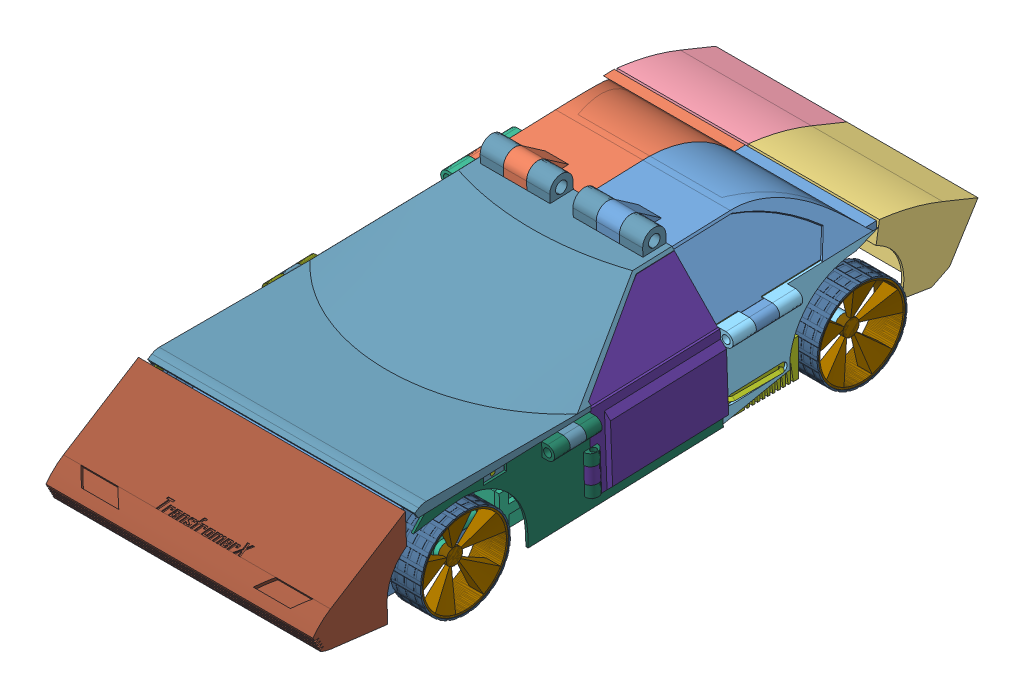
SolidWorks assembly TransformerX_CarMode, configuration Default. Lengths in mm.
Overall size (126 89.14 292.38).
45 component instances, 25 part files, 125 mates.
Components (placement in the parent):
- Body-1: Body [Default] at (-0.7166 15 158.0396) x (1 0 0) z (0 -1 0) size (90 111.5 41.19)
- Leg2_left-1: Leg2_left [Default] at (34.7834 15 123.3396) x (1 0 0) z (0 -1 0) size (33 44.2 22.31)
- Leg2_right-1: Leg2_right [Default] at (-36.2166 15 123.3396) x (1 0 0) z (0 -1 0) size (33 44.2 22.31)
- Head-1: Head [Default] at (-0.7166 15 243.0396) x (1 0 0) z (0 -1 0) size (26 20 18.29)
- Axis-1: Axis [Default] at (34.7834 15 116.1396) x (0 -1 0) z (-1 0 0) size (7 7 39)
- Axis-2: Axis [Default] at (-36.2166 15 116.1396) x (0 -0.62043 -0.784262) z (-1 0 0) size (7 7 39)
- Arm-4: Arm [Default] at (-45.2166 18.6049 182.2607) x (-1 0 0) z (0 0.981511 0.191408) size (24 60 17)
- Arm-5: Arm [Default] at (43.7834 12.2258 181.5547) x (1 0 0) z (0 -0.999612 -0.027841) size (24 60 17)
- Leg1-1: Leg1 [Default] at (34.7834 11 91.5396) x (1 0 0) z (0 -1 0) size (44.5 80.02 25)
- Leg1-2: Leg1 [Default] at (-36.2166 11 91.5396) x (1 0 0) z (0 -1 0) size (44.5 80.02 25)
- Axis-3: Axis [Default] at (-36.2166 11 49.6396) x (0 0.287561 -0.957762) z (-1 0 0) size (7 7 39)
- Axis-4: Axis [Default] at (34.7834 11 49.6396) x (0 -0.62043 -0.784262) z (-1 0 0) size (7 7 39)
- Locker-1: Locker [Default] at (51.2834 15 116.1396) x (0 0.975545 0.219799) z (1 0 0) size (9 9 4)
- Locker-2: Locker [Default] at (-52.7166 15 116.1396) x (0 -0.822687 -0.568495) z (-1 0 0) size (9 9 4)
- Locker-3: Locker [Default] at (-19.7166 15 116.1396) x (0 0.518621 0.855004) z (1 0 0) size (9 9 4)
- Locker-4: Locker [Default] at (18.2834 15 116.1396) x (0 0.991738 -0.128282) z (-1 0 0) size (9 9 4)
- Wheel-1: Wheel [Default] at (-54.4666 11 49.6396) x (0 0.974851 0.222857) z (-1 0 0) size (37.5 37.5 12.5)
- Wheel-2: Wheel [Default] at (-17.9666 11 49.6396) x (0 0.657679 0.753298) z (1 0 0) size (37.5 37.5 12.5)
- Wheel-3: Wheel [Default] at (16.5334 11 49.6396) x (0 -0.657679 -0.753298) z (-1 0 0) size (37.5 37.5 12.5)
- Wheel-4: Wheel [Default] at (53.0334 11 49.6396) x (0 0.657679 0.753298) z (1 0 0) size (37.5 37.5 12.5)
- Wheel-5: Wheel [Default] at (53.0334 11.14 220.5396) x (0 -0.683817 0.729653) z (1 0 0) size (37.5 37.5 12.5)
- Wheel-6: Wheel [Default] at (-54.4666 11.14 220.5396) x (0 0.512398 -0.858748) z (-1 0 0) size (37.5 37.5 12.5)
- Tire-1: Tire [Default] at (16.5334 11 49.6396) x (0 -0.314731 -0.949181) z (1 0 0) size (38.8 38.79 13)
- Tire-2: Tire [Default] at (-54.4666 11 49.6396) x (0 0.805468 -0.59264) z (1 0 0) size (38.8 38.79 13)
- Tire-3: Tire [Default] at (-17.9666 11 49.6396) x (0 0.068791 0.997631) z (-1 0 0) size (38.8 38.79 13)
- Tire-4: Tire [Default] at (-54.4666 11.14 220.5396) x (0 0.968779 -0.247928) z (1 0 0) size (38.8 38.79 13)
- Tire-5: Tire [Default] at (53.0334 11 49.6396) x (0 0.314731 0.949181) z (-1 0 0) size (38.8 38.79 13)
- Tire-6: Tire [Default] at (53.0334 11.14 220.5396) x (0 -0.756586 0.653895) z (-1 0 0) size (38.8 38.79 13)
- CarPart1-1: CarPart1 [Default] at (-0.7166 21.0613 251.9185) x (0 -0.03628 0.999342) z (-1 0 0) size (40.79 38 115)
- Axis3-1: Axis3 [Default] at (45.0334 30 247.0396) x (0 1 0) z (1 0 0) size (8 8 19.5)
- Axis3-2: Axis3 [Default] at (-46.4666 30 247.0396) x (0 -0.381849 0.924225) z (-1 0 0) size (8 8 19.5)
- Locker2-2: Locker2 [Default] at (-36.7166 30 247.0396) x (0 -0.99661 0.082275) z (-1 0 0) size (8 8 4)
- Locker2-3: Locker2 [Default] at (35.2834 30 247.0396) x (0 0.456595 -0.889675) z (1 0 0) size (8 8 4)
- CarPart2-1: CarPart2 [Default] at (-0.7166 37.5573 174.212) x (0 -0.03628 0.999342) z (-1 0 0) size (131.64 36.94 126)
- CarPart3_left-1: CarPart3_left [Default] at (56.2834 7.3112 163.3576) x (0 -0.03628 0.999342) z (-1 0 0) size (132.4 36.62 6.5)
- CarPart3_right-1: CarPart3_right [Default] at (-57.7166 7.3112 163.3576) x (0 -0.03628 0.999342) z (-1 0 0) size (132.4 36.62 6.5)
- CarPart_Door_left-1: CarPart_Door_left [Default] at (56.7834 22.7866 135.6508) x (0 -0.03628 0.999342) z (-1 0 0) size (59.5 53.92 22.75)
- CarPart_Door_right-1: CarPart_Door_right [Default] at (-57.2166 22.7866 135.6508) x (0 -0.03628 0.999342) z (-1 0 0) size (59.5 53.92 22.75)
- CarPart4_left-1: CarPart4_left [Default] at (27.5334 42.2028 73.8145) x (0 -0.03628 0.999342) z (-1 0 0) size (78.5 35.5 63)
- CarPart4_right-1: CarPart4_right [Default] at (-28.9666 42.2028 73.8145) x (0 -0.03628 0.999342) z (-1 0 0) size (78.5 35.5 63)
- CarPart5_left-1: CarPart5_left [Default] at (27.5334 41.5302 25.0024) x (0 -0.158579 -0.987346) z (1 0 0) size (48.5 32.62 56.5)
- CarPart5_right-1: CarPart5_right [Default] at (-28.9666 41.5302 25.0024) x (0 -0.158579 -0.987346) z (1 0 0) size (48.5 32.62 56.5)
- CarPart6_left-1: CarPart6_left [Default] at (55.7834 23.4142 72.8822) x (0 -0.03628 0.999342) z (-1 0 0) size (69 37.62 7.5)
- CarPart6_right-1: CarPart6_right [Default] at (-56.2166 23.4142 72.8822) x (0 -0.03628 0.999342) z (-1 0 0) size (69 37.62 7.5)
- Axis4-1: Axis4 [Default] at (-0.7166 35 205.0396) x (0 0 1) z (-1 0 0) size (5.5 5.5 113)
Mates (geometry in assembly coordinates):
- Concentric1: concentric aligned: cylinder of Body-1 through (27.2834 15 147.8396) axis (-1 0 0) radius 3.5; cylinder of Leg2_left-1 through (27.2834 15 147.8396) axis (-1 0 0) radius 3.5
- Coincident1: coincident anti-aligned: plane of Body-1 through (27.2834 15 147.8396) normal (1 0 0); plane of Leg2_left-1 through (27.2834 15 147.8396) normal (-1 0 0)
- Concentric2: concentric aligned: cylinder of Body-1 through (-28.7166 15 147.8396) axis (1 0 0) radius 3.5; cylinder of Leg2_right-1 through (-28.7166 15 147.8396) axis (1 0 0) radius 3.5
- Coincident2: coincident anti-aligned: plane of Body-1 through (-28.7166 15 147.8396) normal (-1 0 0); plane of Leg2_right-1 through (-28.7166 15 147.8396) normal (1 0 0)
- Parallel1: parallel aligned: plane of Leg2_left-1 through (18.2834 25 155.3396) normal (0 1 0); plane of Leg2_right-1 through (-52.7166 25 155.3396) normal (0 1 0)
- Parallel2: parallel aligned: plane of Body-1 through (44.2834 30 243.0396) normal (0 1 0); plane of Leg2_right-1 through (-52.7166 25 155.3396) normal (0 1 0)
- Concentric3: concentric aligned: cylinder of Body-1 through (-0.7166 15 250.0396) axis (0 0 -1) radius 4.5; cylinder of Head-1 through (-0.7166 15 250.0396) axis (0 0 -1) radius 4.5
- Coincident5: coincident anti-aligned: plane of Body-1 through (-0.7166 15 250.0396) normal (0 0 1); plane of Head-1 through (-0.7166 15 250.0396) normal (0 0 -1)
- Parallel3: parallel aligned: plane of Body-1 through (-45.7166 0 243.0396) normal (0 -1 0); plane of Head-1 through (-0.7166 4.5 243.0396) normal (0 -1 0)
- Concentric4: concentric anti-aligned: cylinder of Leg2_right-1 through (-19.7166 15 116.1396) axis (-1 0 0) radius 3.5; cylinder of Axis-2 through (-14.84 15 116.1396) axis (1 0 0) radius 3.5
- Coincident7: coincident aligned: plane of Leg2_right-1 through (-19.7166 25 155.3396) normal (1 0 0); plane of Axis-2 through (-19.7166 13.4489 114.1789) normal (1 0 0)
- Concentric5: concentric anti-aligned: cylinder of Leg2_left-1 through (51.2834 15 116.1396) axis (-1 0 0) radius 3.5; cylinder of Axis-1 through (56.16 15 116.1396) axis (1 0 0) radius 3.5
- Coincident8: coincident aligned: plane of Leg2_left-1 through (51.2834 25 155.3396) normal (1 0 0); plane of Axis-1 through (51.2834 12.5 116.1396) normal (1 0 0)
- Concentric6: concentric aligned: cylinder of Body-1 through (30.2834 11.14 220.5396) axis (1 0 0) radius 3.5; cylinder of Arm-5 through (30.2834 11.14 220.5396) axis (1 0 0) radius 3.5
- Coincident9: coincident anti-aligned: plane of Body-1 through (39.2834 30.0011 158.0396) normal (1 0 0); plane of Arm-5 through (39.2834 12.2258 181.5547) normal (-1 0 0)
- Concentric7: concentric aligned: cylinder of Body-1 through (-31.7166 11.14 220.5396) axis (-1 0 0) radius 3.5; cylinder of Arm-4 through (-31.7166 11.14 220.5396) axis (-1 0 0) radius 3.5
- Coincident10: coincident anti-aligned: plane of Body-1 through (-40.7166 30.0011 158.0396) normal (-1 0 0); plane of Arm-4 through (-40.7166 18.6049 182.2607) normal (1 0 0)
- Concentric8: concentric aligned: cylinder of Axis-1 through (56.16 15 116.1396) axis (1 0 0) radius 3.5; cylinder of Leg1-1 through (15.0324 15 116.1396) axis (1 0 0) radius 3.75
- Coincident11: coincident anti-aligned: plane of Leg2_left-1 through (46.7834 15 123.3396) normal (-1 0 0); plane of Leg1-1 through (46.7834 15 116.1396) normal (1 0 0)
- Concentric9: concentric anti-aligned: cylinder of Axis-2 through (-14.84 15 116.1396) axis (1 0 0) radius 3.5; cylinder of Leg1-2 through (-16.4656 15 116.1396) axis (-1 0 0) radius 3.75
- Coincident12: coincident anti-aligned: plane of Leg2_right-1 through (-24.2166 15 123.3396) normal (-1 0 0); plane of Leg1-2 through (-24.2166 15 116.1396) normal (1 0 0)
- Parallel4: parallel aligned: plane of Leg1-1 through (20.7834 19 61.9396) normal (0 1 0); plane of Leg1-2 through (-50.2166 19 61.9396) normal (0 1 0)
- Parallel5: parallel aligned: plane of Leg2_left-1 through (18.2834 25 155.3396) normal (0 1 0); plane of Leg1-1 through (20.7834 19 61.9396) normal (0 1 0)
- Concentric10: concentric anti-aligned: cylinder of Leg1-2 through (-16.4656 11 49.6396) axis (-1 0 0) radius 3.5; cylinder of Axis-3 through (-14.84 11 49.6396) axis (1 0 0) radius 3.5
- Width2: width aligned: plane of Leg1-2 through (-32.2166 3 44.1396) normal (1 0 0); plane of Leg1-2 through (-40.2166 3 44.1396) normal (-1 0 0); plane of Axis-3 through (-19.7166 11.7189 47.2452) normal (1 0 0); plane of Axis-3 through (-52.7166 12.0065 46.2874) normal (-1 0 0)
- Concentric11: concentric anti-aligned: cylinder of Leg1-1 through (54.5344 11 49.6396) axis (-1 0 0) radius 3.5; cylinder of Axis-4 through (56.16 11 49.6396) axis (1 0 0) radius 3.5
- Width3: width aligned: plane of Leg1-1 through (30.7834 3 44.1396) normal (-1 0 0); plane of Leg1-1 through (38.7834 3 44.1396) normal (1 0 0); plane of Axis-4 through (18.2834 8.8285 46.8946) normal (-1 0 0); plane of Axis-4 through (51.2834 9.4489 47.6789) normal (1 0 0)
- Concentric12: concentric aligned: cylinder of Axis-2 through (-14.84 15 116.1396) axis (1 0 0) radius 2.5; cylinder of Locker-2 through (-56.7166 15 116.1396) axis (1 0 0) radius 4.5
- Coincident15: coincident anti-aligned: plane of Leg2_right-1 through (-52.7166 25 155.3396) normal (-1 0 0); plane of Locker-2 through (-52.7166 15 116.1396) normal (1 0 0)
- Concentric13: concentric anti-aligned: cylinder of Axis-1 through (56.16 15 116.1396) axis (1 0 0) radius 2.5; cylinder of Locker-1 through (55.2834 15 116.1396) axis (-1 0 0) radius 4.5
- Coincident16: coincident anti-aligned: plane of Leg2_left-1 through (51.2834 25 155.3396) normal (1 0 0); plane of Locker-1 through (51.2834 15 116.1396) normal (-1 0 0)
- Concentric14: concentric anti-aligned: cylinder of Axis-2 through (-14.84 15 116.1396) axis (1 0 0) radius 2.5; cylinder of Locker-3 through (-15.7166 15 116.1396) axis (-1 0 0) radius 4.5
- Coincident17: coincident anti-aligned: plane of Leg2_right-1 through (-19.7166 25 155.3396) normal (1 0 0); plane of Locker-3 through (-19.7166 15 116.1396) normal (-1 0 0)
- Concentric15: concentric aligned: cylinder of Axis-1 through (56.16 15 116.1396) axis (1 0 0) radius 2.5; cylinder of Locker-4 through (15.2834 15 116.1396) axis (1 0 0) radius 2.5
- Coincident18: coincident anti-aligned: plane of Leg2_left-1 through (18.2834 25 155.3396) normal (-1 0 0); plane of Locker-4 through (18.2834 15 116.1396) normal (1 0 0)
- Concentric16: concentric aligned: cylinder of Axis-3 through (-14.84 11 49.6396) axis (1 0 0) radius 2.5; cylinder of Wheel-1 through (-55.7166 11 49.6396) axis (1 0 0) radius 2.5
- Coincident19: coincident anti-aligned: plane of Axis-3 through (-52.7166 12.0065 46.2874) normal (-1 0 0); plane of Wheel-1 through (-52.7166 7.588 48.8596) normal (1 0 0)
- Concentric17: concentric anti-aligned: cylinder of Axis-3 through (-14.84 11 49.6396) axis (1 0 0) radius 2.5; cylinder of Wheel-2 through (-16.7166 11 49.6396) axis (-1 0 0) radius 2.5
- Coincident20: coincident anti-aligned: plane of Axis-3 through (-19.7166 11.7189 47.2452) normal (1 0 0); plane of Wheel-2 through (-19.7166 8.6981 47.003) normal (-1 0 0)
- Concentric18: concentric aligned: cylinder of Axis-4 through (56.16 11 49.6396) axis (1 0 0) radius 2.5; cylinder of Wheel-3 through (15.2834 11 49.6396) axis (1 0 0) radius 2.5
- Coincident21: coincident anti-aligned: plane of Axis-4 through (18.2834 8.8285 46.8946) normal (-1 0 0); plane of Wheel-3 through (18.2834 13.3019 52.2761) normal (1 0 0)
- Concentric19: concentric anti-aligned: cylinder of Axis-4 through (56.16 11 49.6396) axis (1 0 0) radius 2.5; cylinder of Wheel-4 through (54.2834 11 49.6396) axis (-1 0 0) radius 2.5
- Coincident22: coincident anti-aligned: plane of Axis-4 through (51.2834 9.4489 47.6789) normal (1 0 0); plane of Wheel-4 through (51.2834 8.6981 47.003) normal (-1 0 0)
- Concentric20: concentric aligned: cylinder of Arm-4 through (-55.7166 11.14 220.5396) axis (1 0 0) radius 2.5; cylinder of Wheel-6 through (-55.7166 11.14 220.5396) axis (1 0 0) radius 2.5
- Coincident23: coincident anti-aligned: plane of Arm-4 through (-52.7166 11.14 220.5396) normal (-1 0 0); plane of Wheel-6 through (-52.7166 9.3466 223.5452) normal (1 0 0)
- Concentric21: concentric aligned: cylinder of Arm-5 through (54.2834 11.14 220.5396) axis (-1 0 0) radius 2.5; cylinder of Wheel-5 through (54.2834 11.14 220.5396) axis (-1 0 0) radius 2.5
- Coincident24: coincident anti-aligned: plane of Arm-5 through (51.2834 11.14 220.5396) normal (1 0 0); plane of Wheel-5 through (51.2834 13.5334 217.9858) normal (-1 0 0)
- Parallel6: parallel aligned: plane of Wheel-3 through (16.5334 11.639 49.5848) normal (0 -0.996343 0.085446); plane of Wheel-4 through (53.0334 11.639 49.5848) normal (0 -0.996343 0.085446)
- Parallel7: parallel aligned: plane of Wheel-1 through (-54.4666 11.639 49.5848) normal (0 -0.996343 0.085446); plane of Wheel-2 through (-17.9666 11.639 49.5848) normal (0 -0.996343 0.085446)
- Parallel8: parallel aligned: plane of Wheel-2 through (-17.9666 11.639 49.5848) normal (0 -0.996343 0.085446); plane of Wheel-3 through (16.5334 11.639 49.5848) normal (0 -0.996343 0.085446)
- Concentric22: concentric anti-aligned: cylinder of Wheel-1 through (-19.3072 11 49.6396) axis (1 0 0) radius 18.75; cylinder of Tire-2 through (-47.9656 11 49.6396) axis (-1 0 0) radius 18.75
- Width4: width aligned: plane of Wheel-1 through (-60.7166 11 49.6396) normal (-1 0 0); plane of Wheel-1 through (-48.2166 -7.2785 45.461) normal (1 0 0); plane of Tire-2 through (-60.9666 11 49.6396) normal (-1 0 0); plane of Tire-2 through (-47.9666 11 49.6396) normal (1 0 0)
- Concentric23: concentric anti-aligned: cylinder of Wheel-2 through (-53.126 11 49.6396) axis (-1 0 0) radius 18.75; cylinder of Tire-3 through (-24.4676 11 49.6396) axis (1 0 0) radius 18.75
- Width5: width aligned: plane of Wheel-2 through (-11.7166 11 49.6396) normal (1 0 0); plane of Wheel-2 through (-24.2166 -1.3315 35.5152) normal (-1 0 0); plane of Tire-3 through (-11.4666 11 49.6396) normal (1 0 0); plane of Tire-3 through (-24.4666 11 49.6396) normal (-1 0 0)
- Concentric24: concentric anti-aligned: cylinder of Wheel-3 through (51.6928 11 49.6396) axis (1 0 0) radius 18.75; cylinder of Tire-1 through (23.0344 11 49.6396) axis (-1 0 0) radius 18.75
- Width6: width aligned: plane of Wheel-3 through (22.7834 23.3315 63.7639) normal (1 0 0); plane of Wheel-3 through (10.2834 11 49.6396) normal (-1 0 0); plane of Tire-1 through (23.0334 11 49.6396) normal (1 0 0); plane of Tire-1 through (10.0334 11 49.6396) normal (-1 0 0)
- Concentric25: concentric anti-aligned: cylinder of Wheel-4 through (17.874 11 49.6396) axis (-1 0 0) radius 18.75; cylinder of Tire-5 through (46.5324 11 49.6396) axis (1 0 0) radius 18.75
- Width7: width aligned: plane of Wheel-4 through (46.7834 -1.3315 35.5152) normal (-1 0 0); plane of Wheel-4 through (59.2834 11 49.6396) normal (1 0 0); plane of Tire-5 through (46.5334 11 49.6396) normal (-1 0 0); plane of Tire-5 through (59.5334 11 49.6396) normal (1 0 0)
- Concentric26: concentric anti-aligned: cylinder of Wheel-6 through (-19.3072 11.14 220.5396) axis (1 0 0) radius 18.75; cylinder of Tire-4 through (-47.9656 11.14 220.5396) axis (-1 0 0) radius 18.75
- Concentric27: concentric anti-aligned: cylinder of Wheel-5 through (17.874 11.14 220.5396) axis (-1 0 0) radius 18.75; cylinder of Tire-6 through (46.5324 11.14 220.5396) axis (1 0 0) radius 18.75
- Width8: width anti-aligned: plane of Wheel-5 through (59.2834 11.14 220.5396) normal (1 0 0); plane of Wheel-5 through (46.7834 23.9616 206.8586) normal (-1 0 0); plane of Tire-6 through (46.5334 11.14 220.5396) normal (-1 0 0); plane of Tire-6 through (59.5334 11.14 220.5396) normal (1 0 0)
- Width9: width aligned: plane of Wheel-6 through (-60.7166 11.14 220.5396) normal (-1 0 0); plane of Wheel-6 through (-48.2166 1.5325 236.6411) normal (1 0 0); plane of Tire-4 through (-60.9666 11.14 220.5396) normal (-1 0 0); plane of Tire-4 through (-47.9666 11.14 220.5396) normal (1 0 0)
- Parallel9: parallel aligned: plane of Wheel-4 through (53.0334 11.6386 49.5798) normal (0 -0.995653 0.093145); plane of Tire-5 through (53.0334 11 49.6396) normal (0 -0.995653 0.093145)
- Parallel10: parallel aligned: plane of Wheel-3 through (16.5334 11.6386 49.5798) normal (0 -0.995653 0.093145); plane of Tire-1 through (16.5334 11 49.6396) normal (0 -0.995653 0.093145)
- Parallel11: parallel aligned: plane of Wheel-2 through (-17.9666 11.6386 49.5798) normal (0 -0.995653 0.093145); plane of Tire-3 through (-17.9666 11 49.6396) normal (0 -0.995653 0.093145)
- Parallel12: parallel aligned: plane of Wheel-1 through (-54.4666 11.2541 50.2284) normal (0 -0.39626 -0.918139); plane of Tire-2 through (-54.4666 11 49.6396) normal (0 -0.39626 -0.918139)
- Parallel13: parallel aligned: plane of Wheel-5 through (53.0334 11.4147 219.96) normal (0 -0.428369 0.903604); plane of Tire-6 through (53.0334 11.14 220.5396) normal (0 -0.428369 0.903604)
- Parallel14: parallel anti-aligned: plane of Wheel-6 through (-54.4666 11.2848 219.9147) normal (0 -0.225718 0.974193); plane of Tire-4 through (-54.4666 11.14 220.5396) normal (0 0.225718 -0.974193)
- Concentric28: concentric anti-aligned: cylinder of Body-1 through (-45.7877 30 247.0396) axis (1 0 0) radius 2.5; cylinder of CarPart1-1 through (54.7834 30 247.0396) axis (-1 0 0) radius 2.5
- Width10: width anti-aligned: plane of Body-1 through (44.2834 0 243.0396) normal (1 0 0); plane of Body-1 through (-45.7166 30 243.0396) normal (-1 0 0); plane of CarPart1-1 through (-58.2166 10.8466 231.5345) normal (-1 0 0); plane of CarPart1-1 through (56.7834 10.8466 231.5345) normal (1 0 0)
- Concentric30: concentric aligned: cylinder of CarPart1-1 through (54.7834 30 247.0396) axis (-1 0 0) radius 2.5; cylinder of Axis3-1 through (16.5008 30 247.0396) axis (-1 0 0) radius 2.5
- Coincident36: coincident anti-aligned: plane of Body-1 through (41.2834 30 247.0396) normal (1 0 0); plane of Axis3-1 through (41.2834 32.5 247.0396) normal (-1 0 0)
- Concentric31: concentric anti-aligned: cylinder of Body-1 through (-31.6456 30 247.0396) axis (-1 0 0) radius 2.5; cylinder of Axis3-2 through (-17.934 30 247.0396) axis (1 0 0) radius 2.5
- Coincident37: coincident anti-aligned: plane of CarPart1-1 through (-54.2166 29.9565 248.2388) normal (1 0 0); plane of Axis3-2 through (-54.2166 28.4726 250.7365) normal (-1 0 0)
- Concentric32: concentric anti-aligned: cylinder of Axis3-2 through (-17.934 30 247.0396) axis (1 0 0) radius 2.5; cylinder of Locker2-2 through (-36.7166 30 247.0396) axis (-1 0 0) radius 2.5
- Coincident38: coincident anti-aligned: plane of Body-1 through (-38.7166 30 247.0396) normal (1 0 0); plane of Locker2-2 through (-38.7166 30 247.0396) normal (-1 0 0)
- Concentric34: concentric aligned: cylinder of Locker2-3 through (-106.1457 30 247.0396) axis (-1 0 0) radius 4; cylinder of Axis3-1 through (16.5008 30 247.0396) axis (-1 0 0) radius 2.5
- Coincident39: coincident anti-aligned: plane of Body-1 through (37.2834 30 247.0396) normal (-1 0 0); plane of Locker2-3 through (37.2834 30 247.0396) normal (1 0 0)
- Parallel15: parallel aligned: plane of Body-1 through (44.2834 30 243.0396) normal (0 1 0); plane of CarPart2-1 through (127.7422 39.7254 234.6611) normal (0 1 0)
- Width12: width anti-aligned: plane of Body-1 through (39.2834 30.0011 158.0396) normal (1 0 0); plane of Body-1 through (-40.7166 30.0011 158.0396) normal (-1 0 0); plane of CarPart2-1 through (-58.2166 37.1524 240.491) normal (-1 0 0); plane of CarPart2-1 through (56.7834 39.556 174.2846) normal (1 0 0)
- Concentric36: concentric aligned: cylinder of CarPart2-1 through (59.2834 34.2346 183.0471) axis (0 0.03628 -0.999342) radius 1.75; cylinder of CarPart3_left-1 through (59.2834 33.9897 189.7926) axis (0 0.03628 -0.999342) radius 1.75
- Coincident42: coincident anti-aligned: plane of CarPart2-1 through (59.2834 34.4141 178.1006) normal (0 -0.03628 0.999342); plane of CarPart3_left-1 through (59.2834 34.4141 178.1006) normal (0 0.03628 -0.999342)
- Concentric37: concentric aligned: cylinder of CarPart2-1 through (-60.7166 34.2346 183.0471) axis (0 0.03628 -0.999342) radius 1.75; cylinder of CarPart3_right-1 through (-60.7166 33.9897 189.7926) axis (0 0.03628 -0.999342) radius 1.75
- Coincident43: coincident anti-aligned: plane of CarPart2-1 through (-60.7166 34.6681 171.1052) normal (0 0.03628 -0.999342); plane of CarPart3_right-1 through (-60.7166 34.6681 171.1052) normal (0 -0.03628 0.999342)
- Concentric38: concentric aligned: cylinder of CarPart3_right-1 through (-59.6166 1.3151 163.1399) axis (0 0.999342 0.03628) radius 1.25; cylinder of CarPart_Door_right-1 through (-59.6166 8.7747 163.4107) axis (0 0.999342 0.03628) radius 1.25
- Coincident46: coincident anti-aligned: plane of CarPart3_right-1 through (-58.2166 19.3033 163.7929) normal (0 -0.999342 -0.03628); plane of CarPart_Door_right-1 through (-58.2166 19.3033 163.7929) normal (0 0.999342 0.03628)
- Parallel16: parallel aligned: plane of Body-1 through (-40.7166 30.0011 158.0396) normal (-1 0 0); plane of CarPart3_right-1 through (-58.2166 5.2944 218.9086) normal (-1 0 0)
- Concentric39: concentric anti-aligned: cylinder of CarPart3_left-1 through (58.1834 27.8332 164.1026) axis (0 -0.999342 -0.03628) radius 1.25; cylinder of CarPart_Door_left-1 through (58.1834 8.7747 163.4107) axis (0 0.999342 0.03628) radius 1.25
- Coincident47: coincident anti-aligned: plane of CarPart3_left-1 through (56.7834 19.3033 163.7929) normal (0 -0.999342 -0.03628); plane of CarPart_Door_left-1 through (55.7834 19.3033 163.7929) normal (0 0.999342 0.03628)
- Parallel17: parallel aligned: plane of Body-1 through (39.2834 30.0011 158.0396) normal (1 0 0); plane of CarPart3_left-1 through (56.7834 5.2944 218.9086) normal (1 0 0)
- Parallel18: parallel aligned: plane of CarPart3_left-1 through (56.7834 5.2944 218.9086) normal (1 0 0); plane of CarPart_Door_left-1 through (59.2834 32.5305 157.7688) normal (1 0 0)
- Parallel19: parallel aligned: plane of CarPart3_right-1 through (-58.2166 5.2944 218.9086) normal (-1 0 0); plane of CarPart_Door_right-1
- Concentric40: concentric aligned: cylinder of CarPart2-1 through (-32.7877 65.2626 113.9275) axis (1 0 0) radius 2.5; cylinder of CarPart4_left-1 through (7.2123 65.2626 113.9275) axis (1 0 0) radius 2.5
- Coincident50: coincident anti-aligned: plane of CarPart2-1 through (14.2834 65.2626 113.9275) normal (1 0 0); plane of CarPart4_left-1 through (14.2834 65.2626 113.9275) normal (-1 0 0)
- Concentric41: concentric aligned: cylinder of CarPart2-1 through (-18.6456 65.2626 113.9275) axis (-1 0 0) radius 2.5; cylinder of CarPart4_right-1 through (-8.6456 65.2626 113.9275) axis (-1 0 0) radius 2.5
- Coincident51: coincident anti-aligned: plane of CarPart2-1 through (-15.7166 65.2626 113.9275) normal (-1 0 0); plane of CarPart4_right-1 through (-15.7166 65.2626 113.9275) normal (1 0 0)
- Parallel20: parallel aligned: plane of CarPart2-1; plane of CarPart4_left-1
- Parallel33: parallel aligned: plane of CarPart2-1 through (-0.7166 65.5796 8.7256) normal (0 0.999342 0.03628); plane of CarPart4_right-1 through (-123.5541 61.9463 108.8038) normal (0 0.999342 0.03628)
- Concentric42: concentric anti-aligned: cylinder of CarPart4_right-1 through (-40.4767 42.4279 40.0504) axis (-1 0 0) radius 0.35; cylinder of CarPart5_right-1 through (-47.4566 42.4279 40.0504) axis (1 0 0) radius 0.35
- Coincident55: coincident anti-aligned: plane of CarPart4_right-1 through (-46.4666 42.4279 40.0504) normal (-1 0 0); plane of CarPart5_right-1 through (-46.4666 42.4279 40.0504) normal (1 0 0)
- Concentric43: concentric anti-aligned: cylinder of CarPart4_left-1 through (14.0434 42.4279 40.0504) axis (1 0 0) radius 0.35; cylinder of CarPart5_left-1 through (11.0233 42.4279 40.0504) axis (-1 0 0) radius 0.35
- Coincident56: coincident anti-aligned: plane of CarPart4_left-1 through (45.0334 42.4279 40.0504) normal (1 0 0); plane of CarPart5_left-1 through (45.0334 42.4279 40.0504) normal (-1 0 0)
- Parallel22: parallel aligned: plane of CarPart5_left-1 through (89.7834 44.4367 23.8239) normal (0 0.926727 -0.375736); plane of CarPart5_right-1 through (33.2834 44.4367 23.8239) normal (0 0.926727 -0.375736)
- Concentric45: concentric anti-aligned: cylinder of CarPart4_right-1 through (-60.7166 38.1454 102.8862) axis (0 0.03628 -0.999342) radius 1.75; cylinder of CarPart6_right-1 through (-60.7166 39.2301 73.0064) axis (0 -0.03628 0.999342) radius 1.75
- Coincident59: coincident anti-aligned: plane of CarPart4_right-1 through (-60.7166 38.6877 87.9463) normal (0 0.03628 -0.999342); plane of CarPart6_right-1 through (-60.7166 38.6877 87.9463) normal (0 -0.03628 0.999342)
- Concentric46: concentric aligned: cylinder of CarPart4_left-1 through (59.2834 38.8673 82.9998) axis (0 -0.03628 0.999342) radius 1.75; cylinder of CarPart6_left-1 through (59.2834 39.2301 73.0064) axis (0 -0.03628 0.999342) radius 1.75
- Coincident60: coincident anti-aligned: plane of CarPart4_left-1 through (59.2834 38.6877 87.9463) normal (0 0.03628 -0.999342); plane of CarPart6_left-1 through (59.2834 38.6877 87.9463) normal (0 -0.03628 0.999342)
- LimitAngle1: limit planar angle = 0 rad aligned: plane of CarPart_Door_right-1 through (-60.7166 32.5305 157.7688) normal (-1 0 0); plane of CarPart3_right-1 through (-58.2166 5.2944 218.9086) normal (-1 0 0)
- Parallel24: parallel aligned: plane of CarPart_Door_left-1 through (106.3768 50.5996 47.626) normal (1 0 0); plane of CarPart6_left-1 through (102.8768 -59.8923 70.6016) normal (1 0 0)
- GearMate1: gear = 2.5 : 2.5 mm: circle of CarPart_Door_right-1; circle of CarPart_Door_left-1
- GearMate4: gear = 3.5 : 3.5 mm: cylinder of CarPart3_left-1 through (106.3768 33.9897 162.78) axis (0 0.03628 -0.999342) radius 1.75; cylinder of CarPart3_right-1 through (-13.6232 33.9897 162.78) axis (0 0.03628 -0.999342) radius 1.75
- LimitAngle2: limit planar angle = 1.570796 rad aligned: plane of CarPart3_right-1 through (-58.2166 5.2944 218.9086) normal (-1 0 0); plane of CarPart2-1 through (127.7422 39.7254 234.6611) normal (0 1 0)
- LimitAngle3: limit planar angle = 1.570796 rad aligned: plane of CarPart6_right-1 through (-57.2166 9.555 47.2769) normal (-1 0 0); plane of CarPart4_right-1 through (-123.5541 61.9463 108.8038) normal (0 0.999342 0.03628)
- GearMate12: gear = 3.5 : 3.5 mm: cylinder of CarPart6_right-1 through (-60.7166 39.2301 73.0064) axis (0 -0.03628 0.999342) radius 1.75; cylinder of CarPart6_left-1 through (59.2834 39.2301 73.0064) axis (0 -0.03628 0.999342) radius 1.75
- GearMate10: gear = 7 : 3.5 mm: cylinder of CarPart6_right-1 through (-13.6232 -33.1442 42.4624) axis (0 0.999999 -0.001715) radius 1.75; cylinder of CarPart2-1 through (28.4479 6.7583 14.8939) axis (-1 0 0) radius 2.5
- Parallel40: parallel aligned: plane of CarPart4_left-1 through (-67.0541 61.9463 108.8038) normal (0 0.999342 0.03628); plane of CarPart4_right-1 through (-123.5541 61.9463 108.8038) normal (0 0.999342 0.03628)
- GearMate17: gear = 7 : 7 mm: cylinder of Leg2_right-1 through (-28.7166 15 147.8396) axis (1 0 0) radius 3.5; cylinder of Leg2_left-1 through (27.2834 15 147.8396) axis (-1 0 0) radius 3.5
- LimitAngle4: limit planar angle = 0 rad aligned: plane of Leg1-2 through (-50.2166 3 61.9396) normal (0 -1 0); plane of Leg2_right-1 through (-48.2166 5 111.1396) normal (0 -1 0)
- LimitAngle5: limit planar angle = 0 rad aligned: plane of Leg1-1 through (20.7834 3 61.9396) normal (0 -1 0); plane of Leg2_left-1 through (22.7834 5 111.1396) normal (0 -1 0)
- Coincident61: coincident: plane of Body-1 through (-45.7166 0 243.0396) normal (0 -1 0); plane of assembly through (0 0 0) normal (0 1 0)
- Angle2: planar angle = 0.421479 rad aligned: plane of CarPart5_right-1 through (33.2834 44.4367 23.8239) normal (0 0.926727 -0.375736); plane of CarPart4_right-1 through (-28.9666 45.2008 73.9233) normal (0 0.999342 0.03628)
- Concentric47: concentric anti-aligned: cylinder of Body-1 through (46.3544 35 205.0396) axis (-1 0 0) radius 2.5; cylinder of CarPart2-1 through (-54.2166 35 205.0396) axis (1 0 0) radius 1.016
- Concentric48: concentric anti-aligned: cylinder of Body-1 through (46.3544 35 205.0396) axis (-1 0 0) radius 2.5; cylinder of Axis4-1 through (70.6973 35 205.0396) axis (1 0 0) radius 2.5
- Coincident62: coincident aligned: plane of CarPart2-1 through (55.7834 35 205.0396) normal (1 0 0); plane of Axis4-1 through (55.7834 35 206.0546) normal (1 0 0)
- Parallel48: parallel aligned: plane of CarPart1-1 through (-58.2166 20.1905 275.9027) normal (0 0.847315 0.53109); plane of CarPart2-1 through (127.7422 37.1524 240.491) normal (0 0.847315 0.53109)
